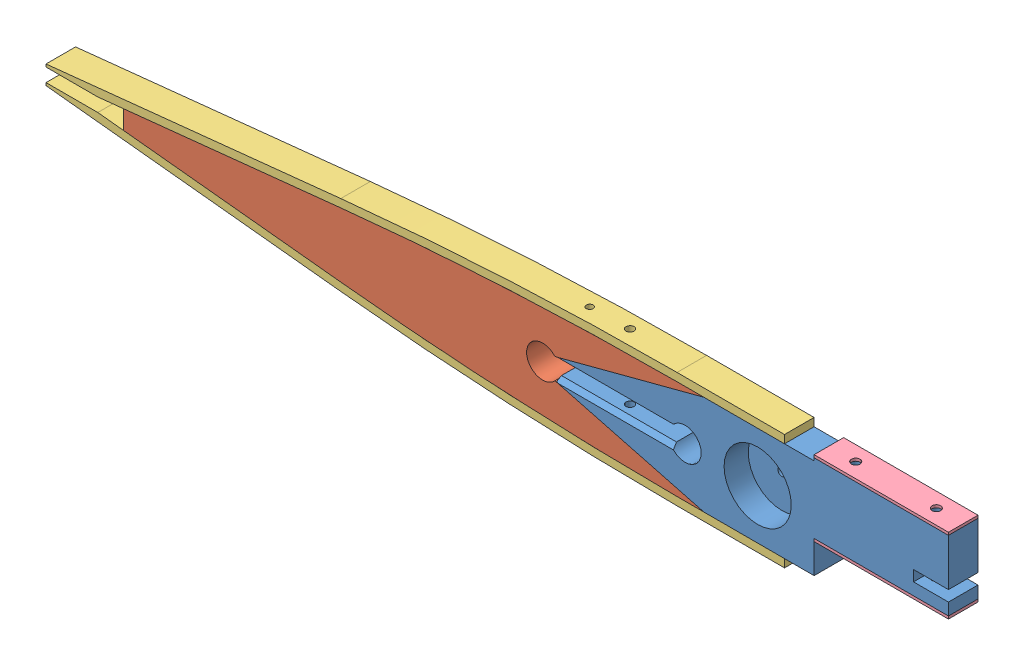
SolidWorks assembly Centersection, configuration Simple. Lengths in mm.
Overall size (335.84 43 137).
11 component instances, 7 part files, 18 mates.
Components (placement in the parent):
- CenterWood-1: CenterWood [Default] at origin
- CenterBalsa-1: CenterBalsa [Default] at origin
- CenterP-1: CenterP [Default] at origin
- CenterP-2: CenterP [Default] x (1 0 0) z (0 0 -1)
- Engine PCB-1: Engine PCB [Default] at (21 19.5 0)
- Engine PCB-2: Engine PCB [Default] at (21 -7.5 0)
- Tank-1: Tank [Default] at (-10 0 6.5) size (41.5 42.25 126) (hidden)
  - TankDisk-1: TankDisk [Default] at origin size (41 41 5)
  - TankMylar-1: TankMylar [Default] at origin size (41.5 41.5 125)
  - TankDisk-2: TankDisk [Default] at (0 0 120) size (41 41 5)
  - TankBalsa-1: TankBalsa [Default] at (10 21.5 -1) x (0 0 1) z (-1 0 0) size (25 5 25)
Mates (geometry in assembly coordinates):
- Coincident1: coincident aligned: plane of CenterWood-1; plane of CenterBalsa-1
- Coincident2: coincident aligned: plane of CenterBalsa-1; plane of assembly
- Coincident3: coincident: point of CenterBalsa-1; point of assembly
- Coincident4: coincident aligned: plane of CenterWood-1; plane of CenterP-1
- Coincident5: coincident aligned: plane of CenterWood-1; plane of CenterP-1
- Coincident6: coincident: point of CenterWood-1; point of CenterP-1
- Coincident7: coincident anti-aligned: plane of CenterWood-1; plane of CenterP-2
- Coincident8: coincident anti-aligned: plane of CenterWood-1; plane of CenterP-2
- Coincident9: coincident: point of CenterWood-1; point of CenterP-2
- Concentric13: concentric anti-aligned: cylinder of CenterWood-1; cylinder of Engine PCB-1
- Coincident20: coincident anti-aligned: plane of CenterWood-1 through (61 19.5 5.5) normal (0 1 0); plane of Engine PCB-1 through (61 19.5 5.5) normal (0 -1 0)
- Concentric14: concentric anti-aligned: cylinder of CenterWood-1; cylinder of Engine PCB-2
- Coincident21: coincident anti-aligned: plane of CenterWood-1 through (61 -6.5 5.5) normal (0 -1 0); plane of Engine PCB-2 through (61 -6.5 5.5) normal (0 1 0)
- Coincident22: coincident aligned: plane of CenterWood-1 through (61 -2 5.5) normal (1 0 0); plane of Engine PCB-2 through (61 -6.5 -5.5) normal (1 0 0)
- Coincident23: coincident aligned: plane of ? through (61 19.5 5.5) normal (1 0 0)
- Coincident32: coincident aligned: plane of CenterP-1 through (0 21.5 5.5) normal (0 1 0); plane of Tank-1/TankBalsa-1 through (-25 21.5 5.5) normal (0 1 0)
- Coincident33: coincident aligned: plane of CenterP-1 through (0 18.5 5.5) normal (1 0 0); plane of Tank-1/TankBalsa-1 through (0 16.5 5.5) normal (1 0 0)
- Coincident35: coincident anti-aligned: plane of CenterP-1 through (-40 -1181.5 5.5) normal (0 0 1); plane of Tank-1/TankBalsa-1 through (0 16.5 5.5) normal (0 0 -1)
